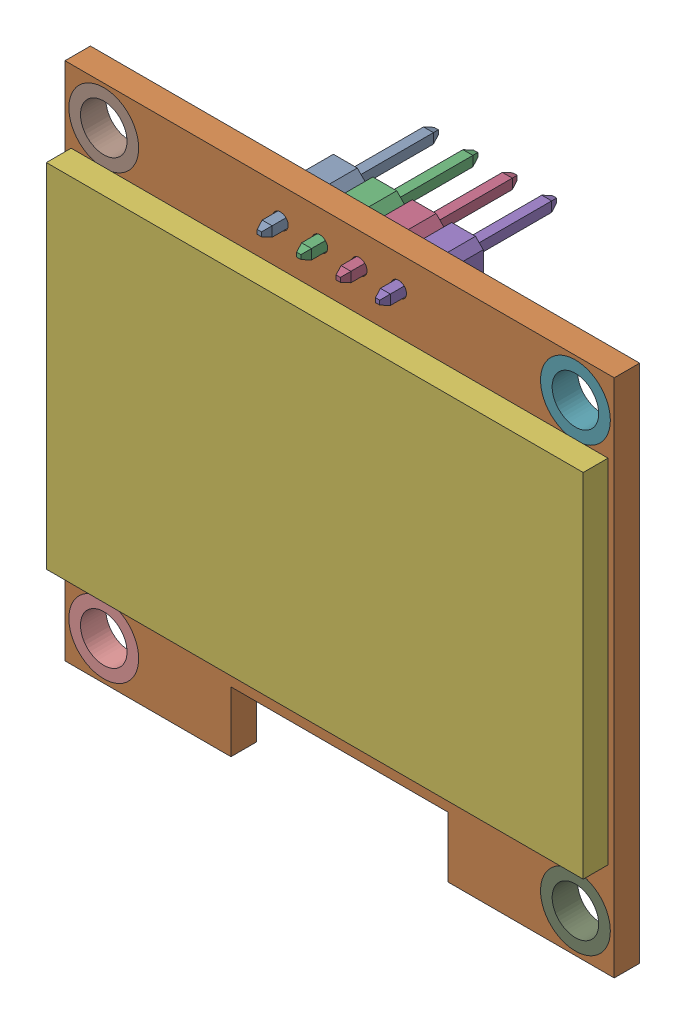
SolidWorks assembly Geekcreit 1.3 Inch 4Pin.step, configuration Default. Lengths in mm.
Overall size (35.4 33.5 11.64).
10 component instances, 7 part files, 0 mates.
Components (placement in the parent):
- 2.54mm_pin_header.step-1: 2.54mm_pin_header.step [Default] at (-6.7934 -64.0536 -112.2285) x (1 0 0) z (0 1 0) size (2.54 11.4 2.5)
- Part 1.step-1: Part 1.step [Default] at (-5.7881 4.8942 0.9376) size (35.4 33.5 1.64)
- 2.54mm_pin_header.step-2: 2.54mm_pin_header.step [Default] at (-4.2534 -64.0536 -112.2285) x (1 0 0) z (0 1 0) size (2.54 11.4 2.5)
- 2.54mm_pin_header.step-3: 2.54mm_pin_header.step [Default] at (-1.7134 -64.0536 -112.2285) x (1 0 0) z (0 1 0) size (2.54 11.4 2.5)
- 2.54mm_pin_header.step-4: 2.54mm_pin_header.step [Default] at (0.8266 -64.0536 -112.2285) x (1 0 0) z (0 1 0) size (2.54 11.4 2.5)
- Part 2.step-1: Part 2.step [Default] at (-5.7881 5.6098 0.9376) size (34.6 22.7 1.64)
- Part 3.step-1: Part 3.step [Default] at (24.6119 4.8942 0.9376) size (4.5 4.5 1.64)
- Part 4.step-1: Part 4.step [Default] at (-36.1881 4.8942 0.9376) size (4.5 4.5 1.64)
- Part 5.step-1: Part 5.step [Default] at (-5.7881 4.8942 0.9376) size (4.5 4.5 1.64)
- Part 6.step-1: Part 6.step [Default] at (-5.7881 4.8942 0.9376) size (4.5 4.5 1.64)
